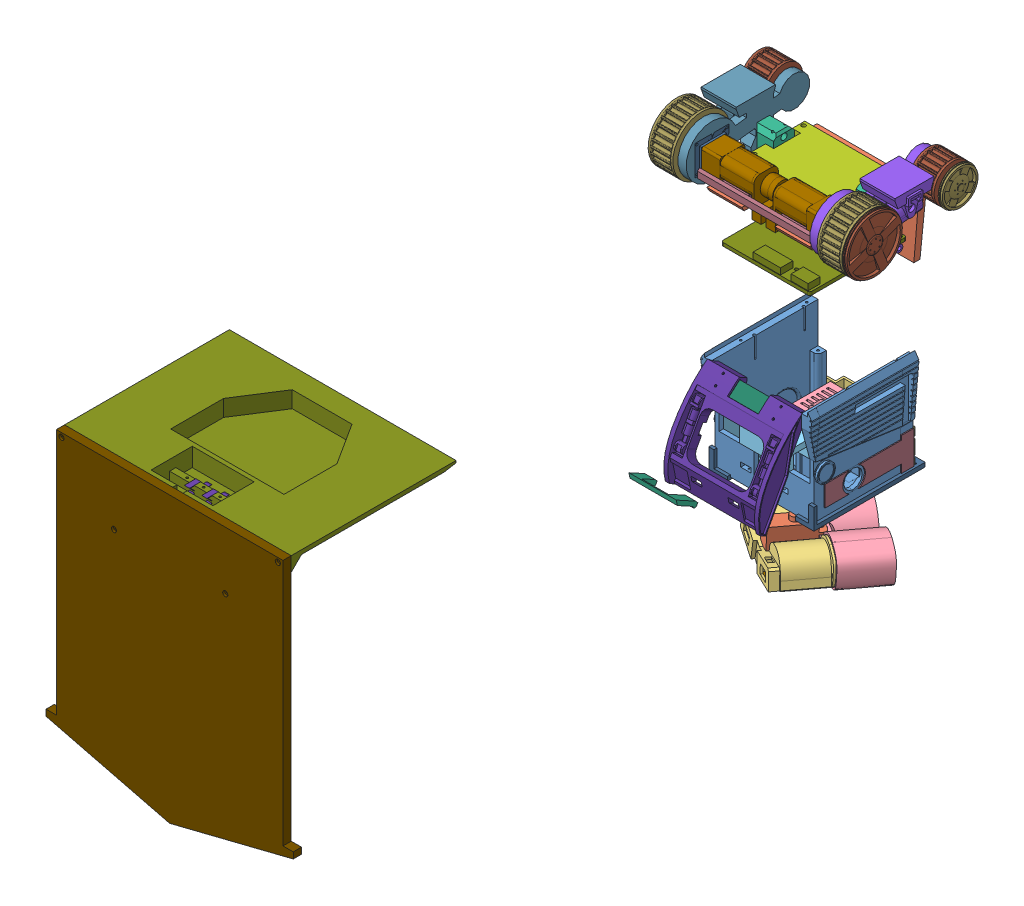
SolidWorks assembly 装配, configuration Default. Lengths in mm.
Overall size (120 189.04 345.59).
42 component instances, 36 part files, 105 mates.
Components (placement in the parent):
- 身体上壳-1: 身体上壳 [Default] at (19.0296 10.5409 31.091) size (53.95 50 52)
- 身体下壳-1: 身体下壳 [Default] at (19.0296 129.6104 32.591) x (-1 0 0) z (0 0 1) size (53 33 55)
- 屏幕支架-1: 屏幕支架 [Default] at (19.0296 19.0409 7.091) x (1 0 0) z (0 1 0) size (48 5 17)
- 舵机固定架-手部俯仰-1: 舵机固定架-手部俯仰 [Default] at (19.0296 20.5409 18.591) x (0 0 1) z (-1 0 0) size (23 15 32)
- 舵机固定架-头部俯仰-1: 舵机固定架-头部俯仰 [Default] at (19.0296 27.0409 48.841) size (24 9 12.5)
- 动力固定架-1: 动力固定架 [Default] at (19.0296 139.6104 25.591) x (1 0 0) z (0 0 -1) size (60 10 10)
- 电池盖123040-1: 电池盖123040 [Default] at (19.0296 134.6104 24.091) x (-1 0 0) z (0 0 1) size (48 5 35)
- 轮托-1: 轮托 [Default] at (49.0296 151.1104 30.591) x (0 0 1) z (0 1 0) size (60 18 33)
- N20-motor_with_encoder-1: N20-motor_with_encoder [Default] at (41.0296 138.6104 50.591) x (0 0 1) z (0 1 0) size (12 40.5 18.05)
- 电机-轮托-固定件-1: 电机-轮托-固定件 [Default] at (53.0296 138.6104 50.591) x (0 0 -1) z (0 1 0) size (16.5 3 14.5)
- 被动轮-20齿-外径18.34-履带-1: 被动轮-20齿-外径18.34-履带 [Default] at (68.0296 143.6104 10.591) x (0 1 0) z (0 0 1) size (18.34 12 18.34)
- 主动轮-30齿-外径27.89-履带-1: 主动轮-30齿-外径27.89-履带 [Default] at (68.0296 138.6104 50.591) x (0 -0.613354 -0.789808) z (0 0.789808 -0.613354) size (27.89 12 27.89)
- 主动轮-30齿-外径27.89-履带-2: 主动轮-30齿-外径27.89-履带 [Default] at (-29.9704 138.6104 50.591) x (0 0.354546 -0.935038) z (0 -0.935038 -0.354546) size (27.89 12 27.89)
- 被动轮-20齿-外径18.34-履带-2: 被动轮-20齿-外径18.34-履带 [Default] at (-13.9704 143.6104 10.591) x (0 0.961702 -0.274097) z (0 0.274097 0.961702) size (18.34 12 18.34)
- 动力固定架-后-1: 动力固定架-后 [Default] at (19.0296 134.6104 50.591) x (1 0 0) z (0 0 -1) size (60 5 14)
- 舵机2.5g-无固定-1: 舵机2.5g-无固定 [Default] at (-2.9704 24.2909 48.866) x (0 -1 0) z (0 0 1) size (19.5 20.3 8.25)
- 舵机2.5g一字臂-截断-1: 舵机2.5g一字臂-截断 [Default] at (18.3296 18.7909 48.866) x (0 -0.959552 0.281532) z (0 -0.281532 -0.959552) size (8.9 4 5.8)
- 主板PCB-1: 主板PCB [Default] at (19.0296 106.8977 31.091) x (0 0 1) z (1 0 0) size (47 4.6 43)
- 后盖-1: 后盖 [Default] at (19.5296 37.3346 66.99) x (-1 0 0) z (0 0.877567 -0.479454) size (46.02 13.26 46)
- 颈部底座-1: 颈部底座 [Default] at (19.0296 10.6409 42.091) x (-1 0 0) z (0 0 1) size (19 15.13 23.96)
- 颈部舵机基座-1: 颈部舵机基座 [Default] at (21.2796 0.0141 28.6305) x (0 0.693999 0.719976) z (0 -0.719976 0.693999) size (8 8.29 18.21)
- 舵机2.5g-单固定-A-1: 舵机2.5g-单固定-A [Default] at (15.8642 -23.3134 40.2261) x (0.530087 -0.058374 -0.845932) z (0.847943 0.036492 0.528829) size (22 20.3 8.25)
- 头部主控-1: 头部主控 [Default] at (21.6474 -28.9417 31.2942) x (-0.847943 -0.036492 -0.528829) z (0 0.997628 -0.068842) size (47.41 23.01 17.89)
- 眼睛-1: 眼睛 [Default] at (21.6474 -28.9417 31.2942) x (0.847943 0.036492 0.528829) z (0 0.997628 -0.068842) size (49.86 21.02 19.76)
- 头部俯仰拉杆-1: 头部俯仰拉杆 [Default] at (20.7796 4.5178 25.6331) x (-1 0 0) z (0 0.919209 -0.393769) size (4.5 28 1)
- 后盖卡扣-1: 后盖卡扣 [Default] at (19.5296 42.5197 111.9376) x (1 0 0) z (0 0.877567 -0.479454) size (23 12.18 2.5)
- 散热风扇1503-1: 散热风扇1503 [Default] at (26.841 -18.0935 45.444) x (-0.835061 -0.209174 -0.508841) z (-0.530087 0.058374 0.845932) size (15 3 15)
- 视觉主控PCB-1: 视觉主控PCB [Default] at (6.312 -19.5309 32.0641) x (0.835061 -0.137298 0.53275) z (-0.147244 -0.988808 -0.024034) size (14 19.7 3)
- 头部盖-1: 头部盖 [Default] at (27.3084 -24.5706 46.1247) x (-0.835061 -0.209174 -0.508841) z (0.530087 -0.058374 -0.845932) size (17 1 20)
- 肩部装饰架-1: 肩部装饰架 [Default] at (19.0296 9.5409 29.591) size (51 10 54)
- 主动轮装饰件-1: 主动轮装饰件 [Default] at (66.0296 138.6104 50.591) x (0 -0.367898 0.929866) z (0 0.929866 0.367898) size (27.89 2.3 27.89)
- 被动轮装饰件-1: 被动轮装饰件 [Default] at (67.5296 143.6104 10.591) x (0 0.878942 -0.476929) z (0 -0.476929 -0.878942) size (18.34 2.41 18.34)
- 肩部装饰-1: 肩部装饰 [Default] at (43.5196 20.5409 38.769) x (0 0 -1) z (0 1 0) size (43 0.5 17)
- 轮托-镜像-2: 轮托-镜像 [Default] at (-10.9704 151.1104 30.591) x (0 0 1) z (0 1 0) size (60 18 33)
- 电机-轮托-固定件-3: 电机-轮托-固定件 [Default] at (-12.9704 138.6104 50.591) x (0 0 1) z (0 1 0) size (16.5 3 14.5)
- N20-motor_with_encoder-3: N20-motor_with_encoder [Default] at (-0.9704 138.6104 50.591) x (0 0 -1) z (0 1 0) size (12 40.5 18.05)
- 充电PCB-1: 充电PCB [Default] at (19.5296 55.8745 62.2464) x (1 0 0) z (0 -0.66066 0.750685) size (30 0.8 7)
- 装配体-充电座-3: 装配体-充电座 [Default] at (-33.8765 206.363 370.9028) x (1 0 0) z (0 0 -1) size (120 138 84)
  - 充电座-底板-1: 充电座-底板 [Default] at (52.9061 50.7525 71.1528) size (110 30 80)
  - 充电粗触片-1: 充电粗触片 [Default] at (47.4061 46.9177 40.468) x (0 0 -1) z (0 -1 0) size (16.65 2.5 26.67)
  - 充电粗触片-2: 充电粗触片 [Default] at (55.9061 46.9177 40.468) x (0 0 -1) z (0 -1 0) size (16.65 2.5 26.67)
  - 充电座-二维码-1: 充电座-二维码 [Default] at (52.9061 50.7525 29.1528) size (120 138 4)
Mates (geometry in assembly coordinates):
- 同心2: concentric: circle of 身体上壳-1; circle of 身体下壳-1
- 同心1: concentric: circle of 身体上壳-1; circle of 身体下壳-1
- 同心3: concentric: circle of 身体上壳-1; circle of 屏幕支架-1
- 同心4: concentric: circle of 身体上壳-1; circle of 屏幕支架-1
- 手部俯仰: concentric: circle of 身体上壳-1; circle of 舵机固定架-手部俯仰-1
- 同心6: concentric: circle of 身体上壳-1; circle of 舵机固定架-手部俯仰-1
- 重合7: coincident: plane of 身体上壳-1 through (19.0296 20.5409 31.091) normal (0 1 0); plane of 舵机固定架-手部俯仰-1 through (19.0296 20.5409 18.591) normal (0 -1 0)
- 同心7: concentric: circle of 身体上壳-1; circle of 舵机固定架-头部俯仰-1
- 同心8: concentric: circle of 身体上壳-1; circle of 舵机固定架-头部俯仰-1
- 【1】舵机固定-头部俯仰: coincident: plane of 身体上壳-1 through (19.0296 27.0409 31.091) normal (0 1 0); plane of 舵机固定架-头部俯仰-1 through (19.0296 27.0409 48.841) normal (0 -1 0)
- 同心10: concentric: circle of 身体下壳-1; circle of 动力固定架-1
- 同心12: concentric: circle of 身体下壳-1; circle of 动力固定架-1
- 重合15: coincident: plane of 身体下壳-1 through (19.0296 129.6104 32.591) normal (0 1 0); plane of 动力固定架-1 through (19.0296 129.6104 25.591) normal (0 -1 0)
- 【2】电池盖装配: coincident: plane of 身体下壳-1 through (19.0296 129.6104 32.591) normal (0 1 0); plane of 电池盖123040-1 through (19.0296 129.6104 24.091) normal (0 -1 0)
- 同心15: concentric: circle of 身体下壳-1; circle of 电池盖123040-1
- 同心17: concentric: circle of 身体下壳-1; circle of 电池盖123040-1
- 【3】动力装配: coincident: plane of 身体上壳-1 through (19.0296 58.5409 31.091) normal (0 1 0); plane of 身体下壳-1 through (19.0296 58.5409 32.591) normal (0 -1 0)
- 轮托安装: concentric: circle of 动力固定架-1; circle of 轮托-1
- 同心19: concentric: circle of 动力固定架-1; circle of 轮托-1
- 重合24: coincident: plane of 动力固定架-1 through (49.0296 129.6104 20.591) normal (1 0 0); plane of 轮托-1 through (49.0296 143.6104 10.591) normal (-1 0 0)
- 同心22: concentric: circle of 轮托-1; circle of 电机-轮托-固定件-1
- 同心23: concentric: circle of 轮托-1; circle of 电机-轮托-固定件-1
- 重合30: coincident: plane of 轮托-1 through (53.0296 143.6104 10.591) normal (1 0 0); plane of 电机-轮托-固定件-1 through (53.0296 138.6104 50.591) normal (1 0 0)
- 同心26: concentric: circle of N20-motor_with_encoder-1; circle of 电机-轮托-固定件-1
- 同心29: concentric: circle of N20-motor_with_encoder-1; circle of 电机-轮托-固定件-1
- 重合35: coincident: plane of N20-motor_with_encoder-1 through (50.0296 138.6104 50.591) normal (1 0 0); plane of 电机-轮托-固定件-1 through (50.0296 138.6104 50.591) normal (-1 0 0)
- 同心30: concentric: circle of N20-motor_with_encoder-1; circle of 主动轮-30齿-外径27.89-履带-1
- 同心31: concentric: circle of 轮托-1; circle of 被动轮装饰件-1
- 距离1: distance = 1 mm: plane of 轮托-1 through (53.0296 143.6104 10.591) normal (1 0 0); plane of 被动轮-20齿-外径18.34-履带-1 through (54.0296 143.6104 10.591) normal (-1 0 0)
- 距离2: distance = 1 mm: plane of 轮托-1 through (53.0296 143.6104 10.591) normal (1 0 0); plane of 主动轮-30齿-外径27.89-履带-1 through (54.0296 138.6104 50.591) normal (-1 0 0)
- 同心34: concentric: circle of 轮托-1; circle of 动力固定架-后-1
- 同心35: concentric: circle of 轮托-1; circle of 动力固定架-后-1
- 重合45: coincident: plane of 轮托-1 through (49.0296 74.5409 10.591) normal (-1 0 0); plane of 动力固定架-后-1 through (49.0296 60.5409 44.591) normal (1 0 0)
- 重合47: coincident: plane of 身体上壳-1 through (19.0296 15.0409 31.091) normal (0 1 0); plane of 舵机2.5g-无固定-1 through (12.0296 15.0409 52.991) normal (0 -1 0)
- 重合48: coincident: plane of 身体上壳-1 through (-2.9704 -54.5743 55.091) normal (1 0 0); plane of 舵机2.5g-无固定-1 through (-2.9704 24.2909 48.866) normal (-1 0 0)
- 重合49: coincident: plane of 身体上壳-1 through (14.0296 -8.3334 44.741) normal (0 0 1); plane of 舵机2.5g-无固定-1 through (12.0296 15.0409 44.741) normal (0 0 -1)
- 同心37: concentric: circle of 舵机2.5g-无固定-1; circle of 舵机2.5g一字臂-截断-1
- 重合51: coincident: plane of 舵机2.5g-无固定-1 through (17.3296 18.7909 48.866) normal (1 0 0); plane of 舵机2.5g一字臂-截断-1 through (17.3296 18.7909 48.866) normal (-1 0 0)
- 同心: concentric: circle of 身体上壳-1; circle of 主板PCB-1
- 同心39: concentric: circle of 身体上壳-1; circle of 主板PCB-1
- 【X】主板PCB安装: coincident: plane of 身体上壳-1 through (19.0296 39.0409 31.091) normal (0 1 0); plane of 主板PCB-1 through (19.0296 39.0409 31.091) normal (0 -1 0)
- 同心40: concentric: circle of 身体上壳-1; circle of 后盖-1
- 重合55: coincident: plane of 身体上壳-1 through (41.0296 -54.5743 55.091) normal (-1 0 0); plane of 后盖-1 through (41.0296 37.3346 66.99) normal (1 0 0)
- 【5】头部装配: coincident: plane of 身体上壳-1 through (19.0296 10.6409 31.091) normal (0 -1 0); plane of 颈部底座-1 through (19.0296 10.6409 42.091) normal (0 1 0)
- 同心43: concentric: circle of 颈部舵机基座-1; circle of 颈部底座-1
- 重合63: coincident: plane of 颈部底座-1 through (16.2796 0.0141 28.6305) normal (1 0 0); plane of 颈部舵机基座-1 through (16.2796 0.0141 28.6305) normal (-1 0 0)
- 同心44: concentric: circle of 颈部舵机基座-1; circle of 舵机2.5g-单固定-A-1
- 重合64: coincident: plane of 颈部舵机基座-1 through (18.7796 -3.3827 34.176) normal (0 -0.997628 0.068842); plane of 舵机2.5g-单固定-A-1 through (18.7796 -3.3827 34.176) normal (0 0.997628 -0.068842)
- 同心45: concentric: circle of 头部主控-1; circle of 眼睛-1
- 同心46: concentric: circle of 头部主控-1; circle of 眼睛-1
- 重合65: coincident: plane of 头部主控-1 through (10.1282 -22.5409 23.6342) normal (0.530087 -0.058374 -0.845932); plane of 眼睛-1 through (33.1667 -21.5494 38.0024) normal (-0.530087 0.058374 0.845932)
- 重合66: coincident: plane of 舵机2.5g-单固定-A-1 through (15.8642 -23.3134 40.2261) normal (0 -0.997628 0.068842); plane of 头部主控-1 through (21.6474 -23.9536 30.95) normal (0 0.997628 -0.068842)
- 重合67: coincident: plane of 舵机2.5g-单固定-A-1 through (14.4586 -7.6585 49.1998) normal (-0.530087 0.058374 0.845932); plane of 头部主控-1 through (7.4207 -12.9496 45.1547) normal (0.530087 -0.058374 -0.845932)
- 重合68: coincident: plane of 舵机2.5g-单固定-A-1 through (24.2652 -8.7385 33.5501) normal (0.847943 0.036492 0.528829); plane of 头部主控-1 through (24.6363 -13.7675 33.3021) normal (-0.847943 -0.036492 -0.528829)
- 同心47: concentric: circle of 颈部舵机基座-1; circle of 头部俯仰拉杆-1
- 重合69: coincident: plane of 颈部舵机基座-1 through (20.2796 3.614 25.1605) normal (1 0 0); line of 头部俯仰拉杆-1 through (20.2796 14.7558 49.5325) axis (0 -0.393769 -0.919209)
- 同心48: concentric: circle of 舵机2.5g一字臂-截断-1; circle of 头部俯仰拉杆-1
- 同心49: concentric: circle of 身体上壳-1; circle of 颈部底座-1
- 同心50: concentric: circle of 身体上壳-1; circle of 颈部底座-1
- 重合71: coincident: plane of 后盖-1 through (26.0296 29.6506 86.2969) normal (0 -0.877567 0.479454); plane of 后盖卡扣-1 through (31.0296 41 107.0703) normal (0 0.877567 -0.479454)
- 重合72: coincident: plane of 后盖-1 through (8.0296 27.8955 87.2558) normal (1 0 0); plane of 后盖卡扣-1 through (8.0296 41 107.0703) normal (-1 0 0)
- 同心52: concentric: circle of 视觉主控PCB-1; circle of 头部主控-1
- 平行8: parallel: plane of 头部主控-1 through (3.8438 -17.3889 21.4685) normal (0.835061 -0.137298 0.53275); plane of 视觉主控PCB-1 through (4.2154 -19.9877 22.0932) normal (-0.835061 0.137298 -0.53275)
- 重合79: coincident: plane of 头部主控-1 through (22.6878 -21.9549 31.464) normal (-0.147244 -0.988808 -0.024034); plane of 视觉主控PCB-1 through (6.312 -19.5309 32.0641) normal (0.147244 0.988808 0.024034)
- 重合80: coincident: plane of 头部主控-1 through (20.5334 -21.5564 30.0865) normal (0.147244 -0.976135 0.159627); plane of 散热风扇1503-1 through (26.841 -18.0935 45.444) normal (-0.147244 0.976135 -0.159627)
- 同心54: concentric: circle of 头部主控-1; circle of 散热风扇1503-1
- 重合82: coincident: point of 头部主控-1; unknown of 头部盖-1
- 同心55: concentric: circle of 头部主控-1; circle of 散热风扇1503-1
- 重合86: coincident: plane of 头部主控-1 through (11.5758 -26.7528 47.2924) normal (0.147244 -0.976135 0.159627); plane of 头部盖-1 through (27.3084 -24.5706 46.1247) normal (0.147244 -0.976135 0.159627)
- 平行12: parallel: plane of 头部主控-1 through (13.8915 -18.0016 51.686) normal (0.530087 -0.058374 -0.845932); plane of 头部盖-1 through (26.6455 -21.4298 59.6782) normal (-0.530087 0.058374 0.845932)
- 重合91: coincident: unknown of 身体上壳-1; unknown of 肩部装饰架-1
- 重合92: coincident: unknown of 身体上壳-1; unknown of 肩部装饰架-1
- 重合93: coincident: plane of 身体上壳-1 through (19.0296 10.5409 31.091) normal (0 -1 0); plane of 肩部装饰架-1 through (19.0296 10.5409 29.591) normal (0 1 0)
- 重合94: coincident: plane of 身体上壳-1 through (43.0296 60.5409 7.091) normal (0 0 -1); plane of 屏幕支架-1 through (19.0296 19.0409 7.091) normal (0 0 1)
- 同心56: concentric: circle of 被动轮-20齿-外径18.34-履带-1; circle of 被动轮装饰件-1
- 同心57: concentric: circle of 主动轮装饰件-1; circle of 主动轮-30齿-外径27.89-履带-1
- 重合95: coincident: plane of 主动轮装饰件-1 through (66.0296 138.6104 50.591) normal (-1 0 0); plane of 主动轮-30齿-外径27.89-履带-1 through (66.0296 138.6104 50.591) normal (1 0 0)
- 重合97: coincident: plane of 身体上壳-1 through (43.0196 10.5409 31.091) normal (1 0 0); plane of 肩部装饰-1 through (43.0196 20.5409 38.769) normal (-1 0 0); line of 身体上壳-1; line of ?
- 平行14: parallel: line of 身体上壳-1 through (43.0296 25.5409 13.091) axis (0 0 1); line of 肩部装饰-1 through (43.5196 25.5409 50.091) axis (0 0 -1)
- 重合99: coincident: plane of 身体上壳-1 through (43.0196 15.5409 13.091) normal (0 0 -1); plane of 肩部装饰-1 through (43.0196 15.5409 13.091) normal (0 0 1)
- 重合100: coincident: plane of 身体上壳-1 through (43.0196 15.5409 13.091) normal (0 1 0); plane of 肩部装饰-1 through (43.0196 15.5409 50.091) normal (0 -1 0)
- 同心58: concentric: circle of 轮托-1; circle of 主动轮-30齿-外径27.89-履带-2
- 同心60: concentric: circle of 电机-轮托-固定件-3; circle of 轮托-镜像-2
- 同心61: concentric: circle of 电机-轮托-固定件-3; circle of 轮托-镜像-2
- 重合108: coincident: plane of 轮托-镜像-2 through (-10.9704 151.1104 30.591) normal (1 0 0); plane of 电机-轮托-固定件-3 through (-10.9704 138.6104 50.591) normal (1 0 0)
- 同心62: concentric: circle of 电机-轮托-固定件-3; circle of N20-motor_with_encoder-3
- 重合109: coincident: plane of 电机-轮托-固定件-3 through (-9.9704 138.6104 50.591) normal (1 0 0); plane of N20-motor_with_encoder-3 through (-9.9704 138.6104 50.591) normal (-1 0 0)
- 平行16: parallel: plane of N20-motor_with_encoder-1 through (50.0296 143.6104 56.591) normal (0 1 0); plane of N20-motor_with_encoder-3 through (-9.9704 133.6104 44.591) normal (0 -1 0)
- 重合111: coincident: plane of 轮托-1 through (53.0296 151.1104 19.7703) normal (0 1 0); plane of 轮托-镜像-2 through (-6.9704 151.1104 19.7703) normal (0 1 0)
- 重合113: coincident: plane of 轮托-1 through (49.0296 143.6104 10.591) normal (-1 0 0); plane of 动力固定架-后-1 through (49.0296 129.6104 43.591) normal (1 0 0)
- 重合114: coincident: plane of 动力固定架-后-1 through (-10.9704 129.6104 43.591) normal (-1 0 0); plane of 轮托-镜像-2 through (-10.9704 151.1104 30.591) normal (1 0 0)
- 同心63: concentric: circle of 被动轮-20齿-外径18.34-履带-2; circle of 轮托-镜像-2
- 同心64: concentric: circle of 主动轮-30齿-外径27.89-履带-2; circle of 轮托-镜像-2
- 距离3: distance = 1 mm: plane of 主动轮-30齿-外径27.89-履带-2 through (-15.9704 138.6104 50.591) normal (1 0 0); plane of 轮托-镜像-2 through (-14.9704 143.6104 10.591) normal (-1 0 0)
- 距离4: distance = 1 mm: plane of 被动轮-20齿-外径18.34-履带-2 through (-15.9704 143.6104 10.591) normal (1 0 0); plane of 轮托-镜像-2 through (-14.9704 143.6104 10.591) normal (-1 0 0)
- 同心65: concentric: circle of 身体上壳-1; circle of 后盖-1
- 同心66: concentric: circle of 后盖-1; circle of 充电PCB-1
- 同心68: concentric: circle of 后盖-1; circle of 充电PCB-1
- 重合119: coincident: plane of 后盖-1 through (19.5296 46.0303 74.6429) normal (0 -0.750685 -0.66066); plane of 充电PCB-1 through (19.5296 56.4751 62.7749) normal (0 0.750685 0.66066)
- 平行22: parallel: plane of 电池盖123040-1 through (19.0296 134.6104 24.091) normal (0 1 0); plane of 装配体-充电座-3/充电座-底板-1 through (19.0296 145.6104 299.75) normal (0 -1 0)
- 平行23: parallel: line of 电池盖123040-1 through (-4.9704 129.7104 6.591) axis (1 0 0); line of 装配体-充电座-3/充电座-底板-1 through (-35.9704 155.6104 259.75) axis (1 0 0)
- 距离9: distance = 2.5 mm: plane of 轮托-1 through (53.0296 151.1104 19.7703) normal (0 1 0); plane of 装配体-充电座-3/充电座-底板-1 through (19.0296 153.6104 299.75) normal (0 -1 0)
- 距离10: distance = 1 mm: plane of 轮托-1 through (49.0296 143.6104 10.591) normal (-1 0 0); plane of 装配体-充电座-3/充电座-底板-1 through (48.0296 145.6104 259.75) normal (1 0 0)
- 同心69: concentric: circle of 动力固定架-后-1; circle of 电机-轮托-固定件-3
- 同心70: concentric: circle of 动力固定架-后-1; circle of 轮托-镜像-2
